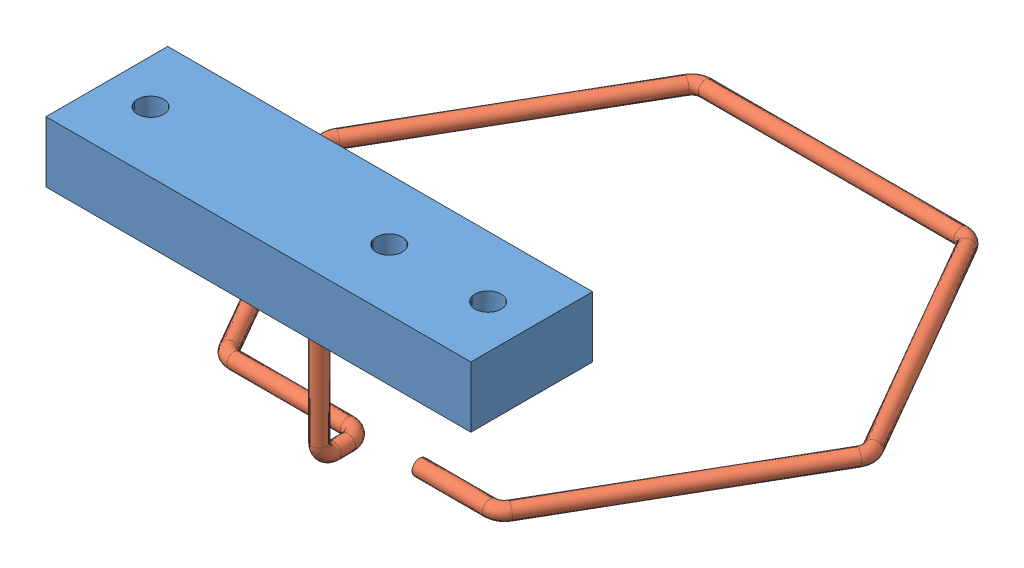
SolidWorks assembly Montagem_Hexagono, configuration Valor predeterminado. Lengths in mm.
Overall size (116.24 47.73 122.06).
2 component instances, 2 part files, 2 mates.
Components (placement in the parent):
- Suporte Arames-1: Suporte Arames [Valor predeterminado] at (41.7157 -6.8855 101.75) size (89 12.75 25.5)
- hexagono-1: hexagono [Valor predeterminado] at (-2.7843 -40.2855 84.5) size (116.24 34.98 110.9)
Mates (geometry in assembly coordinates):
- Concêntrico2: concentric: circle of assembly; circle of hexagono-1; circle of assembly
- Coincidente7: coincident: plane of assembly; plane of assembly; plane of Suporte Arames-1 through (41.7157 -6.8855 101.75) normal (0 -1 0); plane of hexagono-1 through (-2.7843 -6.8855 89) normal (0 1 0)
